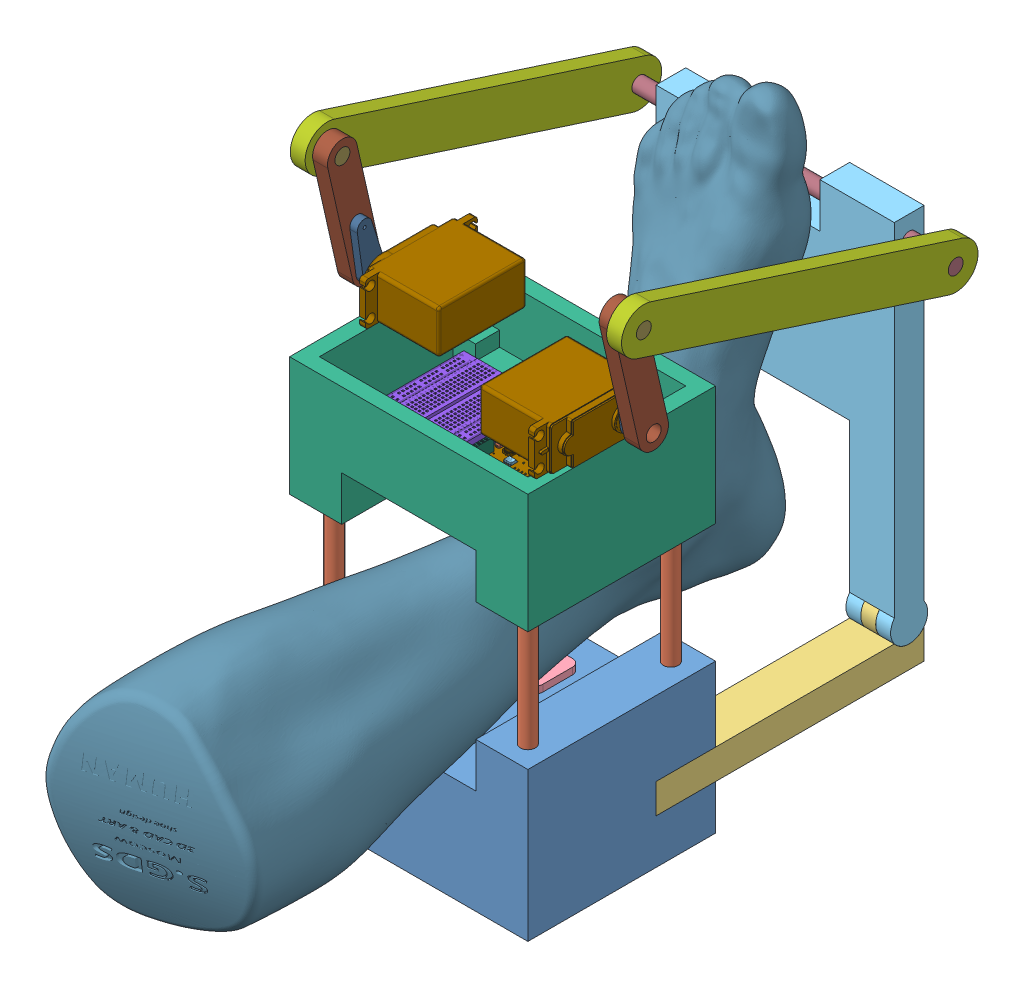
SolidWorks assembly Design103, configuration Default. Lengths in mm.
Overall size (222.4 366.53 465.76).
71 component instances, 32 part files, 57 mates.
Components (placement in the parent):
- Base-1: Base [Default] at (54.0688 54.3707 145.5855) size (160 100 126)
- AdjustmentScrew-1: AdjustmentScrew [Default] at (-10.9312 64.3707 130.5855) x (-0.217507 0 -0.976059) z (0 -1 0) size (10 10 160)
- AdjustmentScrew-2: AdjustmentScrew [Default] at (119.0688 64.3707 130.5855) x (1 0 0) z (0 -1 0) size (10 10 160)
- AdjustmentScrew-3: AdjustmentScrew [Default] at (119.0688 64.3707 34.5855) x (1 0 0) z (0 -1 0) size (10 10 160)
- AdjustmentScrew-4: AdjustmentScrew [Default] at (-10.9312 64.3707 34.5855) x (1 0 0) z (0 -1 0) size (10 10 160)
- ExtensionBase-1: ExtensionBase [Default] at (134.0688 34.3707 59.5855) size (30 40 182.5)
- ExtensionBase-2: ExtensionBase [Default] at (4.0688 34.3707 59.5855) size (30 40 182.5)
- Sensor-1: Sensor [Default] at (54.0688 78.9052 55.5855) size (20 10 30)
- Sensor-2: Sensor [Default] at (54.0688 78.1824 109.5855) size (20 10 30)
- FootBase-1: FootBase [Default] at (54.0688 184.3707 -100.4145) size (160 250 25)
- TopBox-2: TopBox [Default] at (54.0688 224.3707 145.5855) size (160 80 126)
- Connector-3: Connector [Default] at (-57.1312 318.1914 -5.7428) x (1 0 0) z (0 0.307461 0.951561) size (10 30 250)
- Connector-4: Connector [Default] at (165.2688 318.1914 -5.7428) x (-1 0 0) z (0 0.307461 0.951561) size (10 30 250)
- proto_400-2: proto_400 [Default] at (26.0688 224.3707 94.5855) x (1 0 0) z (0 1 0) size (55.3 83.3 10.01)
- Assembly Arduino Uno R3-2: Assembly Arduino Uno R3 [Default] at (52.5044 167.9903 76.8718) x (0 0 1) z (0 1 0) size (75 53.3 16.1)
  - Assembly Arduino Uno R3.STEP-1: Assembly Arduino Uno R3.STEP [Default] at origin size (75 53.3 16.1)
    - 1. Arduino uno PCB.STEP-1: 1. Arduino uno PCB.STEP [Default] at (23.1768 3.2644 56.3804) size (68.53 53.3 1.6)
    - 2. USB.STEP-1: 2. USB.STEP [Default] at (-0.091 39.0544 63.5804) x (0 -1 0) z (-1 0 0) size (14.95 14.22 16.6)
    - 12. Button arduino.STEP-1: 12. Button arduino.STEP [Default] at (-16.3125 58.8663 57.9804) size (8.4 6.2 3)
    - 3. dc jack arduino.STEP-1: 3. dc jack arduino.STEP [Default] at (-15.671 11.3644 63.4804) x (0 1 0) z (1 0 0) size (9.8 16.1 14.4)
    - 4. atmega 328p.STEP-1: 4. atmega 328p.STEP [Default] at (32.929 30.6944 58.7304) x (-1 0 0) z (0 0 -1) size (8.99 8.99 1.2)
    - 2.0  header female 6.STEP-1: 2.0  header female 6.STEP [Default] at (52.3937 64.9176 37.8614) x (0 1 0) z (1 0 0) size (2.54 11.7 15.24)
    - 2.0  header female 8.STEP-1: 2.0  header female 8.STEP [Default] at (34.6337 64.9176 37.8614) x (0 1 0) z (1 0 0) size (2.54 11.7 20.32)
    - 2.0  header female 10.STEP-1: 2.0  header female 10.STEP [Default] at (30.799 113.1576 37.8614) x (0 1 0) z (1 0 0) size (2.54 11.7 25.4)
    - 2.0  header female 8.STEP-2: 2.0  header female 8.STEP [Default] at (52.3946 113.1576 37.8614) x (0 1 0) z (1 0 0) size (2.54 11.7 20.32)
    - 5. header male.STEP-1: 5. header male.STEP [Default] at (56.3437 33.5885 57.9804) x (0 1 0) z (0 0 1) size (7.62 5.08 12.7)
    - 10. cap arduino.STEP-1: 10. cap arduino.STEP [Default] at (12.0737 13.0344 59.9804) x (-1 0 0) z (0 0 -1) size (6 5.3 6.2)
    - 10. cap arduino.STEP-2: 10. cap arduino.STEP [Default] at (4.579 13.0344 59.9804) x (-1 0 0) z (0 0 -1) size (6 5.3 6.2)
    - 8. Arduino part 16MHZ.STEP-1: 8. Arduino part 16MHZ.STEP [Default] at (14.849 43.7344 57.9804) size (13.58 4.8 3.85)
    - 8. Arduino part 16MHZ.STEP-2: 8. Arduino part 16MHZ.STEP [Default] at (41.3137 38.6244 57.9804) x (0 1 0) z (0 0 1) size (13.58 4.8 3.85)
    - 6. diode.STEP-1: 6. diode.STEP [Default] at (11.139 5.7644 59.1804) x (0 1 0) z (0 0 1) size (3.11 5.3 2.43)
    - 13. LM1117.STEP-1: 13. LM1117.STEP [Default] at (-16.299 58.867 57.8807) size (7.32 6.7 1.7)
    - 14. Micro chip part Arduino.STEP-1: 14. Micro chip part Arduino.STEP [Default] at (-16.306 58.8741 57.9804) size (9.9 6 1.75)
    - 7.Lm358 arduino.STEP-1: 7.Lm358 arduino.STEP [Default] at (17.789 18.7444 58.8704) size (6 4.9 1.75)
    - 11. Transistor.STEP-1: 11. Transistor.STEP [Default] at (-16.3121 58.8727 57.9804) size (2.34 2.92 1)
    - 11. Transistor.STEP-2: 11. Transistor.STEP [Default] at (-4.1821 48.9727 57.9804) size (2.34 2.92 1)
    - 9. part.STEP-1: 9. part.STEP [Default] at (19.109 45.7244 58.3804) x (1 0 0) z (0 1 0) size (1.05 0.4 0.55)
    - 9. part.STEP-2: 9. part.STEP [Default] at (19.109 43.3944 58.3804) x (1 0 0) z (0 1 0) size (1.05 0.4 0.55)
    - 9. part.STEP-3: 9. part.STEP [Default] at (19.109 40.6944 58.3804) x (1 0 0) z (0 1 0) size (1.05 0.4 0.55)
    - 9. part.STEP-4: 9. part.STEP [Default] at (19.109 37.9944 58.3804) x (1 0 0) z (0 1 0) size (1.05 0.4 0.55)
    - 9. part.STEP-5: 9. part.STEP [Default] at (19.109 33.0944 58.3804) x (1 0 0) z (0 1 0) size (1.05 0.4 0.55)
    - 9. part.STEP-6: 9. part.STEP [Default] at (19.109 35.4244 58.3804) x (1 0 0) z (0 1 0) size (1.05 0.4 0.55)
    - 9. part.STEP-7: 9. part.STEP [Default] at (19.109 30.4244 58.3804) x (1 0 0) z (0 1 0) size (1.05 0.4 0.55)
    - 9. part.STEP-8: 9. part.STEP [Default] at (19.109 28.1244 58.3804) x (1 0 0) z (0 1 0) size (1.05 0.4 0.55)
    - 9. part.STEP-9: 9. part.STEP [Default] at (19.109 25.7244 58.3804) x (1 0 0) z (0 1 0) size (1.05 0.4 0.55)
    - 9. part.STEP-10: 9. part.STEP [Default] at (19.109 23.4244 58.3804) x (1 0 0) z (0 1 0) size (1.05 0.4 0.55)
    - 15. part 1.STEP-1: 15. part 1.STEP [Default] at (49.8188 35.6465 58.9804) x (0 -1 0) z (1 0 0) size (2.62 1 1.38)
    - 9. part.STEP-11: 9. part.STEP [Default] at (48.0248 40.4298 57.9804) x (0 -1 0) z (-1 0 0) size (1.05 0.4 0.55)
    - 9. part.STEP-12: 9. part.STEP [Default] at (48.0248 36.0298 57.9804) x (0 -1 0) z (-1 0 0) size (1.05 0.4 0.55)
    - 9. part.STEP-13: 9. part.STEP [Default] at (48.0248 31.6298 57.9804) x (0 -1 0) z (-1 0 0) size (1.05 0.4 0.55)
    - 9. part.STEP-14: 9. part.STEP [Default] at (4.3842 45.5109 58.3804) x (1 0 0) z (0 1 0) size (1.05 0.4 0.55)
    - 9. part.STEP-15: 9. part.STEP [Default] at (8.4842 45.5109 58.3804) x (1 0 0) z (0 1 0) size (1.05 0.4 0.55)
    - 9. part.STEP-16: 9. part.STEP [Default] at (12.5842 45.5109 58.3804) x (1 0 0) z (0 1 0) size (1.05 0.4 0.55)
    - 9. part.STEP-17: 9. part.STEP [Default] at (-1.7801 31.2518 58.3804) x (1 0 0) z (0 1 0) size (1.05 0.4 0.55)
    - 9. part.STEP-18: 9. part.STEP [Default] at (-1.7801 28.9518 58.3804) x (1 0 0) z (0 1 0) size (1.05 0.4 0.55)
    - 9. part.STEP-19: 9. part.STEP [Default] at (7.5312 23.47 58.3804) x (1 0 0) z (0 1 0) size (1.05 0.4 0.55)
    - 9. part.STEP-20: 9. part.STEP [Default] at (13.1312 23.47 58.3804) x (1 0 0) z (0 1 0) size (1.05 0.4 0.55)
    - 9. part.STEP-21: 9. part.STEP [Default] at (-0.9044 25.5823 58.3804) x (0 1 0) z (-1 0 0) size (1.05 0.4 0.55)
    - 9. part.STEP-22: 9. part.STEP [Default] at (1.7956 25.5823 58.3804) x (0 1 0) z (-1 0 0) size (1.05 0.4 0.55)
    - 9. part.STEP-23: 9. part.STEP [Default] at (2.1347 17.489 58.3804) x (0 1 0) z (-1 0 0) size (1.05 0.4 0.55)
    - 9. part.STEP-24: 9. part.STEP [Default] at (9.5347 17.489 58.3804) x (0 1 0) z (-1 0 0) size (1.05 0.4 0.55)
- ServoBody-2: ServoBody [Default] at (83.0688 278.8707 97.5855) x (0 0 1) z (0 1 0) size (75 60.2 29)
- ServoBody-3: ServoBody [Default] at (25.0688 278.8707 67.0855) x (0 0 -1) z (0 1 0) size (75 60.2 29)
- ServoArm-2: ServoArm [Default] at (140.2688 278.8707 82.3355) x (0 0.221245 -0.975218) z (0 -0.975218 -0.221245) size (15 8 42.5)
- ServoArm-3: ServoArm [Default] at (-32.1312 278.8707 82.3355) x (0 -0.221245 0.975218) z (0 -0.975218 -0.221245) size (15 8 42.5)
- Link-1: Link [Default] at (145.2688 315.4414 90.6322) x (0 -0.975218 -0.221245) z (-1 0 0) size (95 20 10)
- Link-2: Link [Default] at (-47.1312 315.4414 90.6322) x (0 -0.975218 -0.221245) z (-1 0 0) size (95 20 10)
- JointRodShort-1: JointRodShort [Default] at (165.2688 352.0121 98.9288) x (0 0.751395 -0.659853) z (-1 0 0) size (10 10 20)
- JointRodShort-2: JointRodShort [Default] at (-37.1312 352.0121 98.9288) x (0 0 1) z (-1 0 0) size (10 10 20)
- JointRodLong-1: JointRodLong [Default] at (-57.1312 284.3707 -110.4145) x (0 -0.919944 -0.392049) z (1 0 0) size (10 10 222.4)
- LeftLeg-1: LeftLeg [Default] at (247.0688 269.3707 -100.4145) x (-1 0 0) z (0 1 0) size (134.54 437.6 301.13)
Mates (geometry in assembly coordinates):
- ProfileCenter1: profile center = 0 mm anti-aligned: plane of Base-1 through (-10.9312 64.3707 130.5855) normal (0 1 0); plane of AdjustmentScrew-1 through (-10.9312 64.3707 130.5855) normal (0 -1 0)
- ProfileCenter2: profile center = 0 mm anti-aligned: plane of AdjustmentScrew-2 through (119.0688 64.3707 130.5855) normal (0 -1 0); plane of Base-1 through (119.0688 64.3707 130.5855) normal (0 1 0)
- ProfileCenter3: profile center = 0 mm anti-aligned: plane of AdjustmentScrew-3 through (119.0688 64.3707 34.5855) normal (0 -1 0); plane of Base-1 through (119.0688 64.3707 34.5855) normal (0 1 0)
- ProfileCenter4: profile center = 0 mm anti-aligned: plane of Base-1 through (-10.9312 64.3707 34.5855) normal (0 1 0); plane of AdjustmentScrew-4 through (-10.9312 64.3707 34.5855) normal (0 -1 0)
- Coincident2: coincident anti-aligned: plane of Base-1 through (54.0688 54.3707 59.5855) normal (0 0 -1); plane of ExtensionBase-1 through (104.0688 34.3707 59.5855) normal (0 0 1)
- Coincident3: coincident anti-aligned: plane of Base-1 through (104.0688 34.3707 59.5855) normal (1 0 0); plane of ExtensionBase-1 through (104.0688 34.3707 59.5855) normal (-1 0 0)
- Coincident4: coincident anti-aligned: plane of Base-1 through (134.0688 34.3707 59.5855) normal (0 1 0); plane of ExtensionBase-1 through (104.0688 34.3707 59.5855) normal (0 -1 0)
- Coincident5: coincident anti-aligned: plane of Base-1 through (54.0688 54.3707 59.5855) normal (0 0 -1); plane of ExtensionBase-2 through (-25.9312 34.3707 59.5855) normal (0 0 1)
- Coincident6: coincident anti-aligned: plane of Base-1 through (4.0688 34.3707 59.5855) normal (-1 0 0); plane of ExtensionBase-2 through (4.0688 34.3707 59.5855) normal (1 0 0)
- Coincident7: coincident anti-aligned: plane of Base-1 through (-25.9312 34.3707 59.5855) normal (0 1 0); plane of ExtensionBase-2 through (-25.9312 34.3707 59.5855) normal (0 -1 0)
- Concentric1: concentric anti-aligned: cylinder of Base-1 through (59.0688 4.3707 119.5855) axis (0 -1 0) radius 5; cylinder of Sensor-2 through (59.0688 68.1824 119.5855) axis (0 1 0) radius 5
- Coincident8: coincident anti-aligned: plane of Base-1 through (44.0688 4.3707 94.5855) normal (1 0 0); plane of Sensor-2 through (44.0688 68.1824 124.5855) normal (-1 0 0)
- Concentric2: concentric anti-aligned: cylinder of Base-1 through (59.0688 4.3707 65.5855) axis (0 -1 0) radius 5; cylinder of Sensor-1 through (59.0688 68.9052 65.5855) axis (0 1 0) radius 5
- Coincident9: coincident anti-aligned: plane of Base-1 through (44.0688 4.3707 70.5855) normal (1 0 0); plane of Sensor-1 through (44.0688 68.9052 70.5855) normal (-1 0 0)
- Concentric3: concentric anti-aligned: cylinder of ExtensionBase-1 through (124.0688 61.8707 -110.4145) axis (-1 0 0) radius 12.5; cylinder of FootBase-1 through (124.0688 61.8707 -110.4145) axis (1 0 0) radius 12.5
- Coincident10: coincident anti-aligned: plane of ExtensionBase-2 through (-5.9312 61.8707 -110.4145) normal (1 0 0); plane of FootBase-1 through (-5.9312 61.8707 -110.4145) normal (-1 0 0)
- LimitAngle1: limit planar angle = 1.570796 rad anti-aligned: plane of ExtensionBase-1 through (134.0688 34.3707 59.5855) normal (0 1 0); plane of FootBase-1 through (54.0688 184.3707 -100.4145) normal (0 0 1)
- ProfileCenter7: profile center = 0 mm aligned: plane of AdjustmentScrew-2 through (119.0688 224.3707 130.5855) normal (0 1 0); plane of TopBox-2 through (119.0688 224.3707 130.5855) normal (0 -1 0)
- Coincident25: coincident anti-aligned: plane of TopBox-2 through (9.0688 224.3707 19.5855) normal (0 1 0); plane of proto_400-2 through (26.0688 224.3707 94.5855) normal (0 -1 0)
- Coincident26: coincident anti-aligned: plane of TopBox-2 through (54.0688 224.3707 135.5855) normal (0 0 -1); plane of proto_400-2 through (-0.9312 234.3707 135.5855) normal (0 0 1)
- Coincident31: coincident anti-aligned: plane of TopBox-2 through (54.0688 224.3707 135.5855) normal (0 0 -1); plane of Assembly Arduino Uno R3-2/Assembly Arduino Uno R3.STEP-1/1. Arduino uno PCB.STEP-1 through (60.847 225.9707 135.5855) normal (0 0 1)
- Coincident30: coincident anti-aligned: plane of TopBox-2 through (9.0688 224.3707 19.5855) normal (0 1 0); plane of Assembly Arduino Uno R3-2/Assembly Arduino Uno R3.STEP-1/1. Arduino uno PCB.STEP-1 through (55.7688 224.3707 100.0486) normal (0 -1 0)
- Coincident32: coincident anti-aligned: plane of TopBox-2 through (-0.9312 234.3707 135.5855) normal (1 0 0); plane of proto_400-2 through (-0.9312 234.3707 53.5855) normal (-1 0 0)
- Coincident33: coincident anti-aligned: plane of TopBox-2 through (109.0688 234.3707 135.5855) normal (-1 0 0); plane of Assembly Arduino Uno R3-2/Assembly Arduino Uno R3.STEP-1/1. Arduino uno PCB.STEP-1 through (109.0688 225.9707 131.5229) normal (1 0 0)
- Coincident39: coincident anti-aligned: plane of TopBox-2 through (-25.9312 264.3707 19.5855) normal (0 1 0); plane of ServoBody-2 through (130.0688 264.3707 68.0855) normal (0 -1 0)
- Coincident40: coincident aligned: plane of ServoBody-2 through (124.0688 293.3707 60.0855) normal (-1 0 0); plane of TopBox-2 through (124.0688 184.3707 19.5855) normal (-1 0 0)
- Coincident41: coincident anti-aligned: plane of TopBox-2 through (-25.9312 264.3707 19.5855) normal (0 1 0); plane of ServoBody-3 through (-21.9312 264.3707 96.5855) normal (0 -1 0)
- Coincident42: coincident aligned: plane of ServoBody-3 through (-15.9312 293.3707 104.5855) normal (1 0 0); plane of TopBox-2 through (-15.9312 184.3707 19.5855) normal (1 0 0)
- Concentric10: concentric anti-aligned: cylinder of ServoBody-2 through (143.2688 278.8707 82.3355) axis (-1 0 0) radius 4; cylinder of ServoBody-3 through (-35.1312 278.8707 82.3355) axis (1 0 0) radius 4
- Coincident44: coincident anti-aligned: plane of TopBox-2 through (54.0688 224.3707 29.5855) normal (0 0 1); plane of ServoBody-3 through (25.0688 278.8707 29.5855) normal (0 0 -1)
- Concentric11: concentric anti-aligned: cylinder of ServoBody-2 through (143.2688 278.8707 82.3355) axis (-1 0 0) radius 4; cylinder of ServoArm-2 through (140.2688 278.8707 82.3355) axis (1 0 0) radius 4
- Coincident45: coincident anti-aligned: plane of ServoBody-2 through (143.2688 278.8707 82.3355) normal (1 0 0); circle of ServoArm-2
- Concentric12: concentric anti-aligned: cylinder of ServoBody-3 through (-35.1312 278.8707 82.3355) axis (1 0 0) radius 4; cylinder of ServoArm-3 through (-32.1312 278.8707 82.3355) axis (-1 0 0) radius 4
- Coincident46: coincident anti-aligned: plane of ServoBody-3 through (-35.1312 278.8707 82.3355) normal (-1 0 0); plane of ServoArm-3 through (-35.1312 278.8707 82.3355) normal (1 0 0)
- Coincident47: coincident aligned: plane of ServoArm-2; plane of ServoArm-3
- LimitAngle3: limit planar angle = 1.347706 rad aligned: plane of ServoArm-2 through (140.2688 278.8707 82.3355) normal (0 0.221245 -0.975218); plane of ServoBody-2 through (83.0688 278.8707 97.5855) normal (0 1 0)
- Concentric14: concentric anti-aligned: cylinder of ServoBody-2 through (139.2688 278.8707 82.3355) axis (1 0 0) radius 2; cylinder of Link-1 through (155.2688 278.8707 82.3355) axis (-1 0 0) radius 5
- Coincident49: coincident anti-aligned: plane of ServoArm-2 through (145.2688 278.8707 82.3355) normal (1 0 0); plane of Link-1 through (145.2688 351.6457 100.4685) normal (-1 0 0)
- Coincident50: coincident anti-aligned: plane of ServoArm-2; plane of Link-1
- Concentric15: concentric anti-aligned: line of ServoArm-3 through (-37.1312 278.8707 82.3355) axis (1 0 0); cylinder of Link-2 through (-37.1312 278.8707 82.3355) axis (-1 0 0) radius 5
- Coincident51: coincident anti-aligned: plane of ServoArm-3 through (-37.1312 278.8707 82.3355) normal (-1 0 0); plane of Link-2 through (-37.1312 351.6457 100.4685) normal (1 0 0)
- Coincident52: coincident aligned: plane of ServoArm-3; plane of Link-2
- Concentric16: concentric anti-aligned: cylinder of Link-2 through (-37.1312 351.6457 100.4685) axis (-1 0 0) radius 5; cylinder of JointRodShort-2 through (-57.1312 351.6457 100.4685) axis (1 0 0) radius 5
- Concentric18: concentric anti-aligned: cylinder of Link-1 through (155.2688 351.6457 100.4685) axis (-1 0 0) radius 5; cylinder of JointRodShort-1 through (145.2688 351.6457 100.4685) axis (1 0 0) radius 5
- Concentric19: concentric aligned: cylinder of Connector-4 through (155.2678 351.6457 100.4685) axis (1 0 0) radius 5; cylinder of JointRodShort-1 through (145.2688 351.6457 100.4685) axis (1 0 0) radius 5
- Coincident57: coincident aligned: plane of Link-2 through (-37.1312 351.6457 100.4685) normal (1 0 0); plane of JointRodShort-2 through (-37.1312 351.6457 100.4685) normal (1 0 0)
- Coincident58: coincident aligned: plane of Connector-3 through (-57.1312 351.6457 100.4685) normal (-1 0 0); plane of JointRodShort-2 through (-57.1312 351.6457 100.4685) normal (-1 0 0)
- Coincident59: coincident aligned: plane of Connector-4 through (165.2688 351.6457 100.4685) normal (1 0 0); plane of JointRodShort-1 through (165.2688 351.6457 100.4685) normal (1 0 0)
- Coincident60: coincident aligned: plane of Link-1 through (145.2688 351.6457 100.4685) normal (-1 0 0); plane of JointRodShort-1 through (145.2688 351.6457 100.4685) normal (-1 0 0)
- Concentric20: concentric anti-aligned: cylinder of JointRodLong-1 through (165.2688 284.3662 -108.9914) axis (-1 0 0) radius 5; cylinder of FootBase-1 through (-25.9322 284.3662 -108.9914) axis (1 0 0) radius 5
- Coincident61: coincident aligned: plane of Connector-4 through (165.2688 351.6457 100.4685) normal (1 0 0); plane of JointRodLong-1 through (165.2688 284.3662 -108.9914) normal (1 0 0)
- Concentric25: concentric anti-aligned: cylinder of Connector-4 through (155.2678 284.3662 -108.9914) axis (1 0 0) radius 5; cylinder of JointRodLong-1 through (165.2688 284.3662 -108.9914) axis (-1 0 0) radius 5
- Concentric28: concentric anti-aligned: cylinder of Connector-3 through (-47.1302 351.6457 100.4685) axis (-1 0 0) radius 5; cylinder of JointRodShort-2 through (-57.1312 351.6457 100.4685) axis (1 0 0) radius 5
- Concentric30: concentric aligned: cylinder of Connector-3 through (-47.1302 284.3662 -108.9914) axis (-1 0 0) radius 5; cylinder of JointRodLong-1 through (165.2688 284.3662 -108.9914) axis (-1 0 0) radius 5
- Distance1: distance = 113 mm anti-aligned: plane of LeftLeg-1 through (247.0688 269.3707 -100.4145) normal (-1 0 0); plane of Base-1 through (134.0688 4.3707 19.5855) normal (1 0 0)
- Coincident64: coincident aligned: line of FootBase-1 through (54.0688 184.3043 -99.6312) axis (0 -0.006396 0.99998); unknown of LeftLeg-1
- Distance2: distance = 55 mm anti-aligned: plane of LeftLeg-1 through (247.0688 269.3707 -100.4145) normal (0 1 0); plane of TopBox-2 through (9.0688 214.3707 19.5855) normal (0 -1 0)
